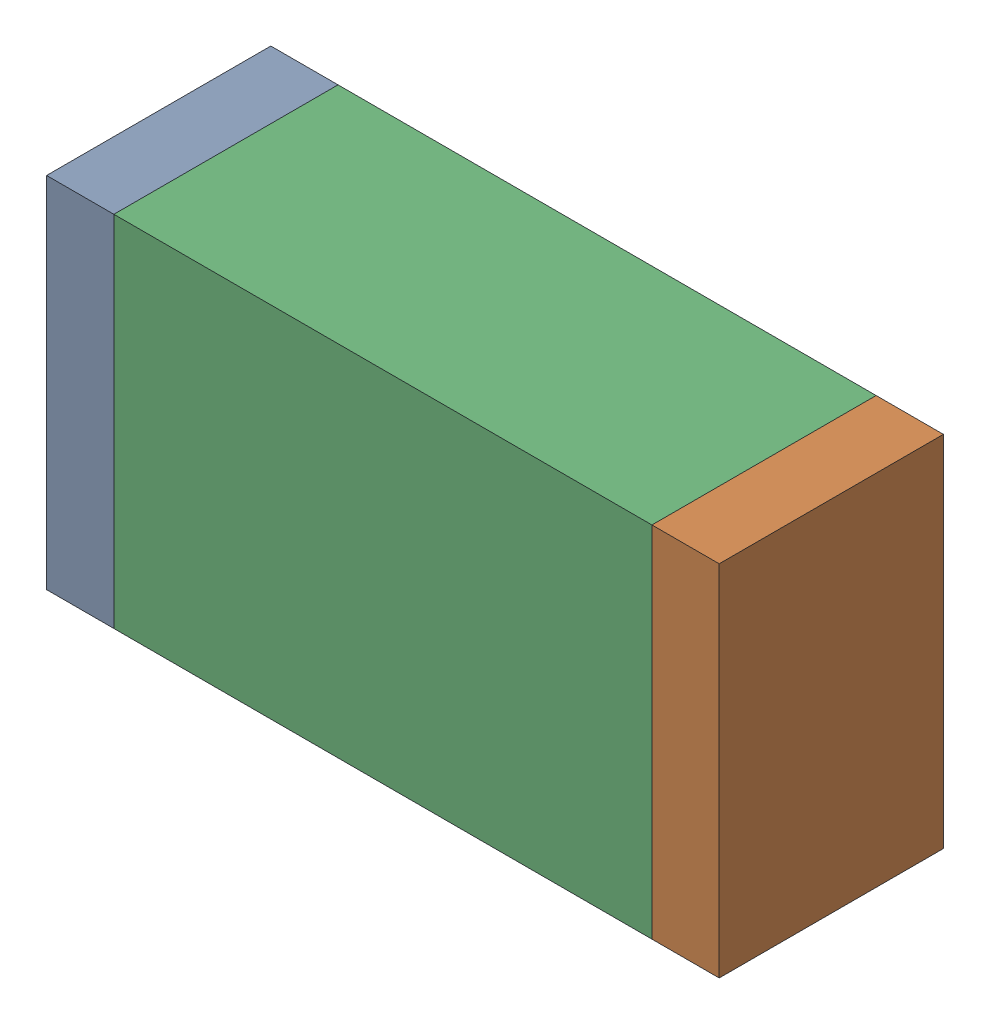
SolidWorks assembly R21, configuration Default. Lengths in mm.
Overall size (1.5 0.8 0.5).
6 component instances, 2 part files, 0 mates.
Components (placement in the parent):
- 836752496-1: 836752496 [Default] at (126.525 43 0) size (0.15 0.8 0.5)
  - Extruded_2-1: Extruded_2 [Default] at origin size (0.15 0.8 0.5)
- 836752496-2: 836752496 [Default] at (127.875 43 0) size (0.15 0.8 0.5)
  - Extruded_2-1: Extruded_2 [Default] at origin size (0.15 0.8 0.5)
- 836752368-1: 836752368 [Default] at (127.2 43 0) size (1.2 0.8 0.5)
  - Extruded-1: Extruded [Default] at origin size (1.2 0.8 0.5)
